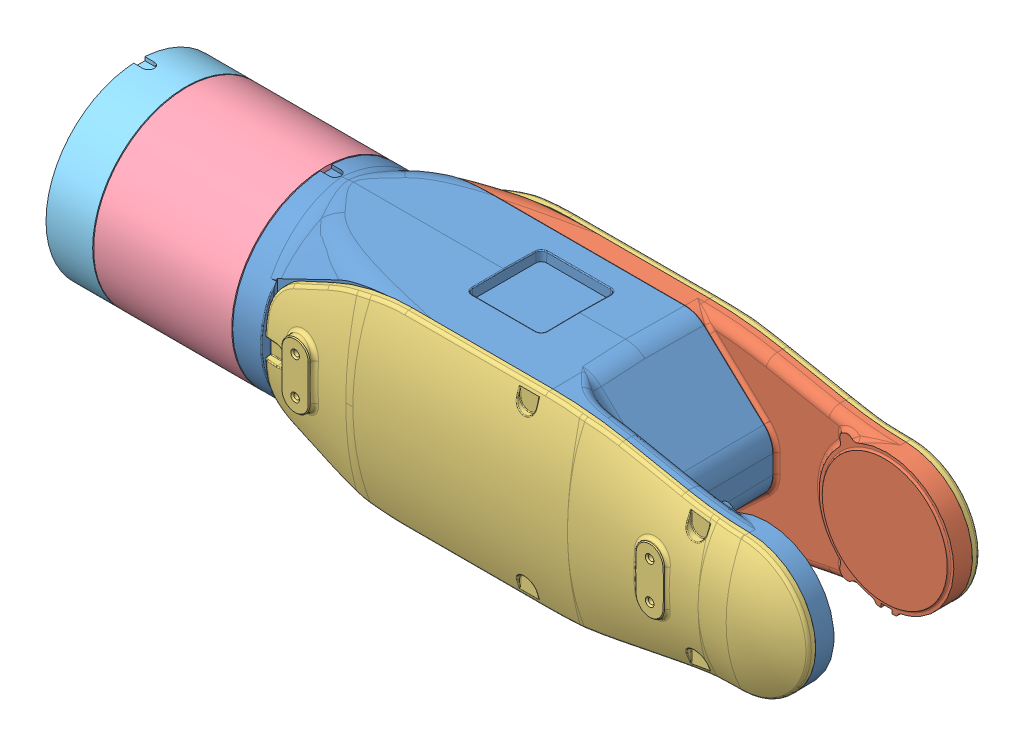
SolidWorks assembly GP7_R_AXIS, configuration Default. Lengths in mm.
Overall size (404.5 107.03 111.12).
6 component instances, 5 part files, 3 mates.
Components (placement in the parent):
- U_ARM-1: U_ARM [Default] at origin size (304.5 107.03 105.62)
- U_ARM2-1: U_ARM2 [Default] at (9.2736 0 -42.3) x (-1 0 0) z (0 0 1) size (288.94 101.3 37.02)
- U_ARM_COVER-1: U_ARM_COVER [Default] at (119.3483 4 61) x (0 -1 0) z (0 0 1) size (100 288.29 16.97)
- UAXIS_SPACER2-1: UAXIS_SPACER2 [Default] at (-141.2517 0 0) x (0 -1 0) z (-1 0 0) size (100 100 82)
- UAXIS_SPACER-1: UAXIS_SPACER [Default] at (-249.1517 0 0) x (-1 0 0) z (0 0 -1) size (28.5 100 100)
- U_ARM_COVER-3: U_ARM_COVER [Default] at (119.3483 -4 -60.999) x (0 1 0) z (0 0 -1) size (100 288.29 16.97)
Mates (geometry in assembly coordinates):
- Coincident1: coincident: plane of HW1200525_U_ARM2-1 through (-5.6518 0 -41.999) normal (0 0 -1); plane of HW1200527_U_ARM_COVER-3 through (119.3483 0 -41.999) normal (0 0 1)
- Concentric1: concentric: cylinder of HW1200525_U_ARM2-1 through (119.3483 0 -33.3656) axis (0 0 -1) radius 36; cone of HW1200527_U_ARM_COVER-3 through (119.3483 0 -41.999) axis (0 0 -1)
- Concentric2: concentric anti-aligned: cone of HW1200527_U_ARM_COVER-1 through (-110.6517 10 54.2) axis (0 0 -1); cone of HW1200527_U_ARM_COVER-3 through (-110.6517 10 -54.199) axis (0 0 1)
